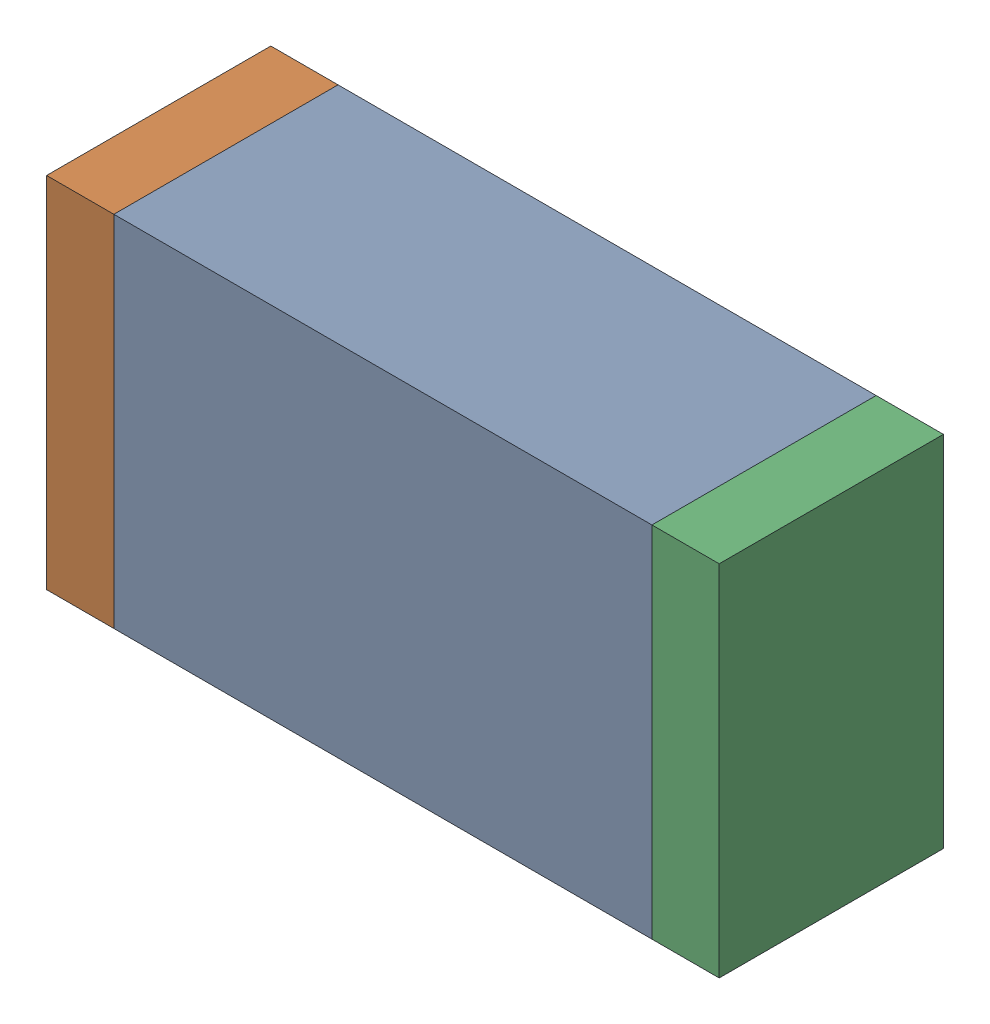
SolidWorks assembly D11, configuration Default. Lengths in mm.
Overall size (1.5 0.8 0.5).
6 component instances, 2 part files, 0 mates.
Components (placement in the parent):
- 836752368-1: 836752368 [Default] at (111.15 26.15 0) size (1.2 0.8 0.5)
  - Extruded-1: Extruded [Default] at origin size (1.2 0.8 0.5)
- 836752496-1: 836752496 [Default] at (110.475 26.15 0) size (0.15 0.8 0.5)
  - Extruded_2-1: Extruded_2 [Default] at origin size (0.15 0.8 0.5)
- 836752496-2: 836752496 [Default] at (111.825 26.15 0) size (0.15 0.8 0.5)
  - Extruded_2-1: Extruded_2 [Default] at origin size (0.15 0.8 0.5)
